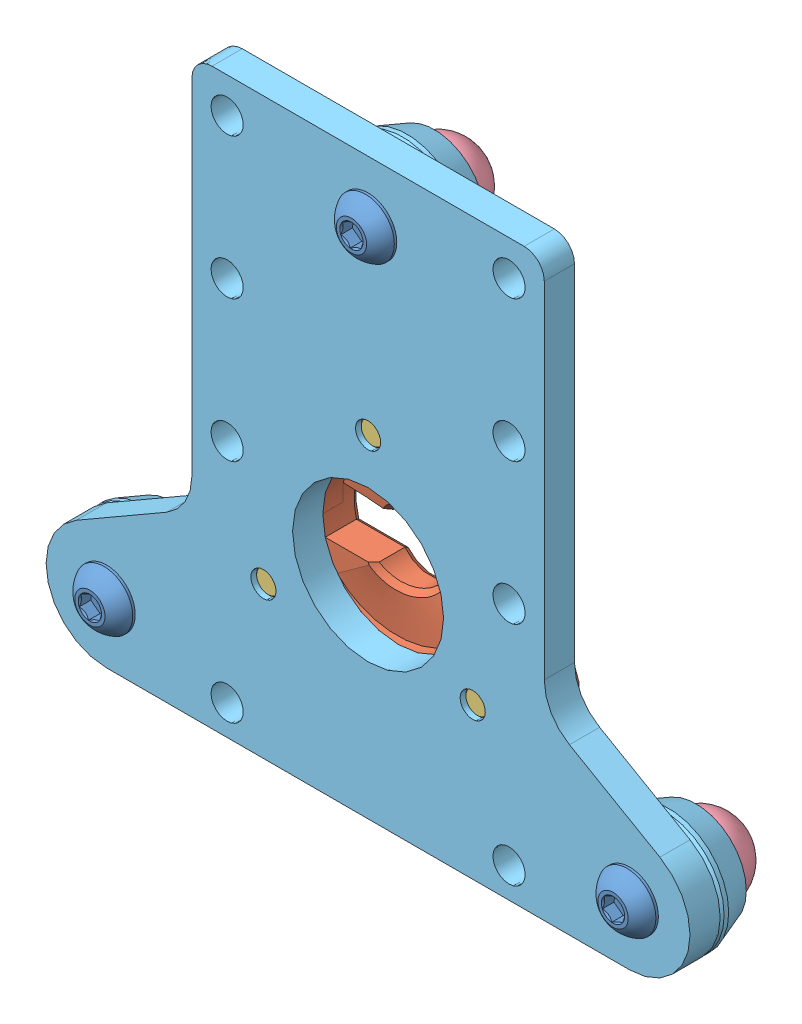
SolidWorks assembly base_tool_plate_assembly, configuration Default. Lengths in mm.
Overall size (111.92 179.7 88.2).
14 component instances, 5 part files, 21 mates.
Components (placement in the parent):
- m3_6mm_buttonhead_screw_92095A179-1: m3_6mm_buttonhead_screw_92095A179 [92095A179] at (49.3311 74.8782 156.133) x (-0.992968 0.118386 0) z (0 0 1)
- wedge_plate-1: wedge_plate [Default] at (23.3504 89.8782 151.483) x (-1 0 0) z (0 0 1)
- m3_6mm_flathead_screw_92125A126-1: m3_6mm_flathead_screw_92125A126 [92125A126] at (33.7427 83.8782 148.033) x (0.923728 0.383049 0) z (0 0 -1)
- m3_6mm_flathead_screw_92125A126-2: m3_6mm_flathead_screw_92125A126 [92125A126] at (23.3504 101.8782 148.033) x (0.923728 0.383049 0) z (0 0 -1)
- m3_6mm_flathead_screw_92125A126-3: m3_6mm_flathead_screw_92125A126 [92125A126] at (12.9581 83.8782 148.033) x (0.923728 0.383049 0) z (0 0 -1)
- m3_threaded_ball-1: m3_threaded_ball [Default] at (1.28 74.0361 147.583) x (-0.210511 -0.977591 0) z (0 0 -1)
- orbiter_base_tool_plate-1: orbiter_base_tool_plate [Tool Plate] at (23.3504 89.8782 151.483)
- m3_threaded_ball-2: m3_threaded_ball [Default] at (51.3747 71.4396 147.583) x (-0.85964 -0.5109 0) z (0 0 -1)
- m3_threaded_ball-3: m3_threaded_ball [Default] at (27.3352 120.2261 147.583) x (0.08699 -0.996209 0) z (0 0 -1)
- m3_6mm_buttonhead_screw_92095A179-2: m3_6mm_buttonhead_screw_92095A179 [92095A179] at (-2.6304 74.8782 156.133) x (-0.992968 0.118386 0) z (0 0 1)
- m3_6mm_buttonhead_screw_92095A179-3: m3_6mm_buttonhead_screw_92095A179 [92095A179] at (23.3504 119.8782 156.133) x (-0.992968 0.118386 0) z (0 0 1)
- orbiter_base_tool_plate-2: orbiter_base_tool_plate [Tool Ball Cup] at (23.3504 89.8782 151.483)
- orbiter_base_tool_plate-3: orbiter_base_tool_plate [Tool Ball Cup] at (49.3311 44.8782 151.483)
- orbiter_base_tool_plate-4: orbiter_base_tool_plate [Tool Ball Cup] at (-2.6304 44.8782 151.483)
Mates (geometry in assembly coordinates):
- Concentric151: concentric anti-aligned: cylinder of orbiter_base_tool_plate-1 through (49.3311 74.8782 154.483) axis (0 0 -1) radius 6; cylinder of m3_6mm_buttonhead_screw_92095A179-1 through (49.3311 74.8782 156.133) axis (0 0 1) radius 2.85
- Coincident371: coincident anti-aligned: plane of orbiter_base_tool_plate-1 through (49.3311 74.8782 154.483) normal (0 0 1); plane of m3_6mm_buttonhead_screw_92095A179-1 through (49.6685 77.7081 154.483) normal (0 0 -1)
- Coincident6: coincident anti-aligned: plane of orbiter_base_tool_plate-1 through (49.3311 74.8782 151.483) normal (0 0 -1); plane of wedge_plate-1 through (23.3504 89.8782 151.483) normal (0 0 1)
- Concentric9: concentric aligned: cylinder of orbiter_base_tool_plate-1 through (23.3504 101.8782 151.483) axis (0 0 -1) radius 1.25; cylinder of wedge_plate-1 through (23.3504 101.8782 147.883) axis (0 0 -1) radius 1.6
- Concentric10: concentric aligned: cylinder of orbiter_base_tool_plate-1 through (12.9581 83.8782 151.483) axis (0 0 -1) radius 1.25; cylinder of wedge_plate-1 through (12.9581 83.8782 147.883) axis (0 0 -1) radius 1.6
- Coincident8: coincident aligned: cone of wedge_plate-1 through (12.9581 83.8782 147.883) axis (0 0 1); cone of m3_6mm_flathead_screw_92125A126-3 through (12.9581 83.8782 149.733) axis (0 0 1)
- Coincident9: coincident aligned: cone of wedge_plate-1 through (23.3504 101.8782 147.883) axis (0 0 1); cone of m3_6mm_flathead_screw_92125A126-2 through (23.3504 101.8782 149.733) axis (0 0 1)
- Coincident10: coincident aligned: cone of wedge_plate-1 through (33.7427 83.8782 147.883) axis (0 0 1); cone of m3_6mm_flathead_screw_92125A126-1 through (33.7427 83.8782 149.733) axis (0 0 1)
- Concentric141: concentric aligned: cylinder of orbiter_base_tool_plate-1 through (-2.6304 74.8782 154.483) axis (0 0 1) radius 1.6; cylinder of m3_6mm_buttonhead_screw_92095A179-2 through (-2.6304 74.8782 156.133) axis (0 0 1) radius 2.85
- Coincident361: coincident anti-aligned: plane of orbiter_base_tool_plate-1 through (49.3311 74.8782 154.483) normal (0 0 1); plane of m3_6mm_buttonhead_screw_92095A179-2 through (-2.293 77.7081 154.483) normal (0 0 -1)
- Concentric16551: concentric aligned: cylinder of orbiter_base_tool_plate-1 through (23.3504 119.8782 154.483) axis (0 0 1) radius 1.6; cylinder of m3_6mm_buttonhead_screw_92095A179-3 through (23.3504 119.8782 156.133) axis (0 0 1) radius 2.85
- Coincident39001: coincident anti-aligned: plane of orbiter_base_tool_plate-1 through (49.3311 74.8782 154.483) normal (0 0 1); plane of m3_6mm_buttonhead_screw_92095A179-3 through (23.6878 122.7081 154.483) normal (0 0 -1)
- Concentric16552: concentric: sphere of m3_threaded_ball-3; sphere of orbiter_base_tool_plate-2
- Coincident39002: coincident anti-aligned: plane of orbiter_base_tool_plate-1 through (49.3311 74.8782 151.483) normal (0 0 -1); plane of orbiter_base_tool_plate-2 through (23.3504 125.8669 151.483) normal (0 0 1)
- Concentric16553: concentric aligned: cylinder of orbiter_base_tool_plate-1 through (23.3504 119.8782 154.483) axis (0 0 1) radius 1.6; cylinder of m3_threaded_ball-3 through (23.3504 119.8782 151.583) axis (0 0 1) radius 1.25
- Concentric16554: concentric: sphere of m3_threaded_ball-2; sphere of orbiter_base_tool_plate-3
- Concentric16555: concentric aligned: cylinder of orbiter_base_tool_plate-1 through (49.3311 74.8782 154.483) axis (0 0 1) radius 1.6; cylinder of m3_threaded_ball-2 through (49.3311 74.8782 151.583) axis (0 0 1) radius 1.25
- Coincident39003: coincident anti-aligned: plane of orbiter_base_tool_plate-1 through (49.3311 74.8782 151.483) normal (0 0 -1); plane of orbiter_base_tool_plate-3 through (49.3311 80.8669 151.483) normal (0 0 1)
- Concentric16556: concentric aligned: cylinder of m3_threaded_ball-1 through (-2.6304 74.8782 151.583) axis (0 0 1) radius 1.25; cylinder of orbiter_base_tool_plate-1 through (-2.6304 74.8782 154.483) axis (0 0 1) radius 1.6
- Coincident39004: coincident anti-aligned: plane of orbiter_base_tool_plate-1 through (49.3311 74.8782 151.483) normal (0 0 -1); plane of orbiter_base_tool_plate-4 through (-2.6304 80.8669 151.483) normal (0 0 1)
- Concentric16557: concentric: sphere of m3_threaded_ball-1; sphere of orbiter_base_tool_plate-4
